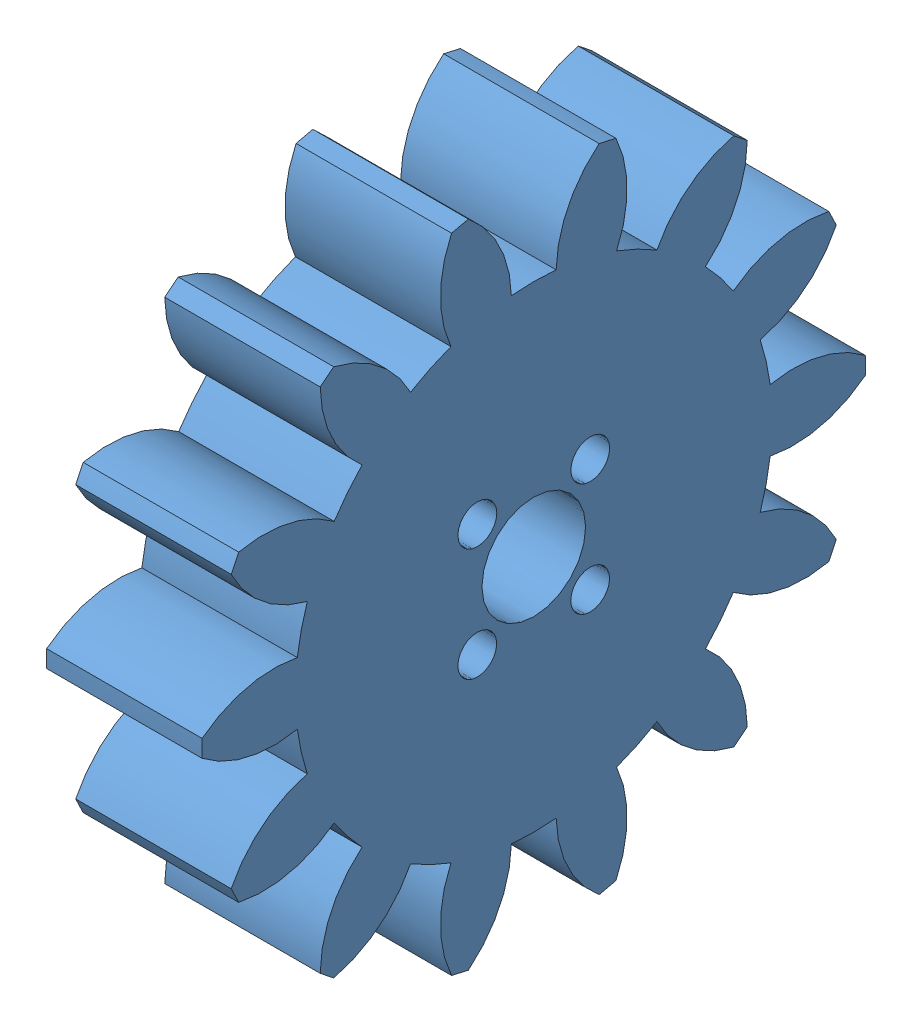
SolidWorks assembly ARMUS-101-500, configuration Défaut. Lengths in mm.
Overall size (28.58 79.69 81.28).
2 component instances, 2 part files, 4 mates.
Components (placement in the parent):
- ARMUS-REV2-501-1: ARMUS-REV2-501 [Défaut] at origin size (19.05 79.69 81.28)
- bore_set_screw_D_hub-1: bore_set_screw_D_hub [Défaut] at (-20.7023 -52.5937 -16.7801) x (0 -1 0.000796) z (0 0.000796 1) size (20.57 9.61 20.57)
Mates (geometry in assembly coordinates):
- Coincident1: coordinate: point of ARMUS-REV2-X01-1
- Concentric1: concentric anti-aligned: cylinder of ARMUS-REV2-X01-1 through (0 -6.91 6.921) axis (1 0 0) radius 2.3813; cylinder of bore_set_screw_D_hub-1 through (0 -6.91 6.921) axis (-1 0 0) radius 3.3722
- Concentric3: concentric anti-aligned: cylinder of ARMUS-REV2-X01-1 through (50.8001 0 0) axis (-1 0 0) radius 6.35; cylinder of bore_set_screw_D_hub-1 through (0 -0.0007 0.0007) axis (1 0 0) radius 3.175
- Coincident2: coincident anti-aligned: plane of ARMUS-REV2-X01-1 through (0 0 0) normal (-1 0 0); plane of bore_set_screw_D_hub-1 through (0 3.4539 -3.4594) normal (1 0 0)
